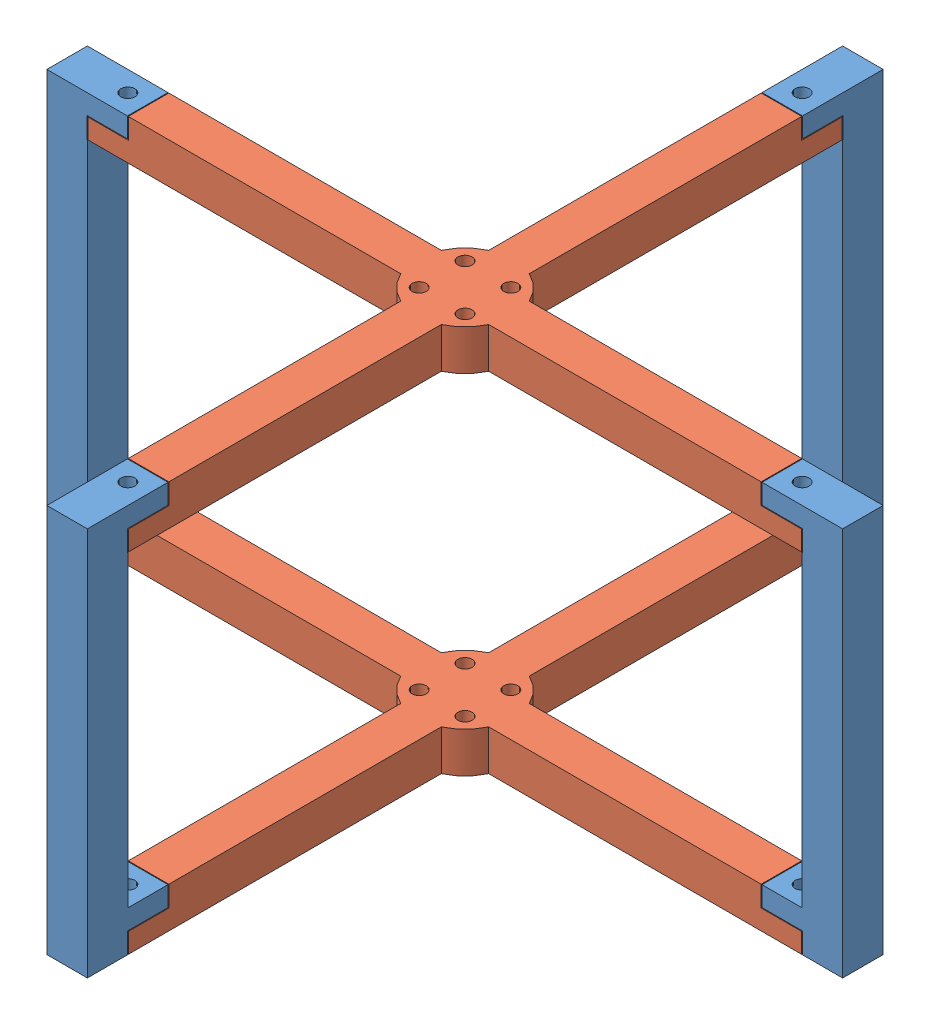
SolidWorks assembly Motor Mount Sub-Assembly, configuration Default. Lengths in mm.
Overall size (196.4 96 196.4).
6 component instances, 2 part files, 17 mates.
Components (placement in the parent):
- Motor Mount Sides-1: Motor Mount Sides [Default] at (110.7628 17.1538 16.3043) size (19.9 96 10)
- Motor Mount Sides-3: Motor Mount Sides [Default] at (27.5628 17.1538 -76.8957) x (0 0 -1) z (1 0 0) size (19.9 96 10)
- Motor Mount Upper-Lower-2: Motor Mount Upper-Lower [Default] at (22.5628 103.1538 11.3043) size (176.2 10 176.2)
- Motor Mount Upper-Lower-3: Motor Mount Upper-Lower [Default] at (22.5628 17.1538 11.3043) size (176.2 10 176.2)
- Motor Mount Sides-4: Motor Mount Sides [Default] at (-65.6372 17.1538 6.3043) x (-1 0 0) z (0 0 -1) size (19.9 96 10)
- Motor Mount Sides-5: Motor Mount Sides [Default] at (17.5628 17.1538 99.5043) x (0 0 1) z (-1 0 0) size (19.9 96 10)
Mates (geometry in assembly coordinates):
- Distance1: distance = 0.2 mm anti-aligned: plane of Motor Mount Sides-1 through (100.8628 108.2538 6.3043) normal (0 -1 0); plane of Motor Mount Upper-Lower-2 through (110.6628 108.0538 -0.6457) normal (0 1 0)
- Parallel1: parallel anti-aligned: plane of Motor Mount Sides-1 through (110.8628 108.2538 6.3043) normal (-1 0 0); plane of Motor Mount Upper-Lower-2 through (110.6628 103.1538 -0.6457) normal (1 0 0)
- Concentric3: concentric anti-aligned: cylinder of Motor Mount Sides-1 through (105.7628 113.1538 11.3043) axis (0 -1 0) radius 1.75; cylinder of Motor Mount Upper-Lower-2 through (105.7628 98.0538 11.3043) axis (0 1 0) radius 1.75
- Parallel2: parallel anti-aligned: plane of Motor Mount Sides-1 through (100.8628 27.1538 6.3043) normal (-1 0 0); plane of Motor Mount Upper-Lower-3 through (110.6628 17.1538 -0.6457) normal (1 0 0)
- Distance2: distance = 0.2 mm anti-aligned: plane of Motor Mount Sides-1 through (110.8628 22.2538 6.3043) normal (-1 0 0); plane of Motor Mount Upper-Lower-3 through (110.6628 17.1538 -0.6457) normal (1 0 0)
- Parallel3: parallel anti-aligned: cylinder of Motor Mount Sides-1 through (105.7628 113.1538 11.3043) axis (0 -1 0) radius 1.75; cylinder of Motor Mount Upper-Lower-3 through (105.7628 12.0538 11.3043) axis (0 1 0) radius 1.75
- Distance3: distance = 0.2 mm anti-aligned: plane of Motor Mount Upper-Lower-3 through (110.6628 22.0538 -0.6457) normal (0 1 0); plane of Motor Mount Sides-1 through (100.8628 22.2538 6.3043) normal (0 -1 0)
- Coincident6: coincident aligned: plane of Motor Mount Sides-1 through (110.7628 17.1538 16.3043) normal (0 0 1); plane of Motor Mount Upper-Lower-3 through (33.4165 -70.7631 16.3043) normal (0 0 1)
- Parallel5: parallel anti-aligned: plane of Motor Mount Sides-3 through (17.5628 113.1538 -66.9957) normal (0 0 1); plane of Motor Mount Upper-Lower-2 through (-75.6372 108.0538 -66.7957) normal (0 0 -1)
- Distance4: distance = 0.2 mm anti-aligned: plane of Motor Mount Sides-3 through (17.5628 108.2538 -66.9957) normal (0 -1 0); plane of Motor Mount Upper-Lower-2 through (-75.6372 108.0538 -76.7957) normal (0 1 0)
- Concentric6: concentric anti-aligned: cylinder of Motor Mount Sides-3 through (22.5628 113.1538 -71.8957) axis (0 -1 0) radius 1.75; cylinder of Motor Mount Upper-Lower-2 through (22.5628 98.0538 -71.8957) axis (0 1 0) radius 1.75
- Parallel6: parallel anti-aligned: plane of Motor Mount Upper-Lower-2 through (-55.5372 108.0538 109.5043) normal (-1 0 0); plane of Motor Mount Sides-4 through (-55.7372 113.1538 16.3043) normal (1 0 0)
- Distance5: distance = 0.2 mm anti-aligned: plane of Motor Mount Sides-4 through (-55.7372 108.2538 16.3043) normal (0 -1 0); plane of Motor Mount Upper-Lower-2 through (-65.5372 108.0538 109.5043) normal (0 1 0)
- Concentric7: concentric anti-aligned: cylinder of Motor Mount Upper-Lower-2 through (-60.6372 98.0538 11.3043) axis (0 1 0) radius 1.75; cylinder of Motor Mount Sides-4 through (-60.6372 113.1538 11.3043) axis (0 -1 0) radius 1.75
- Parallel7: parallel anti-aligned: plane of Motor Mount Upper-Lower-2 through (110.6628 108.0538 89.4043) normal (0 0 1); plane of Motor Mount Sides-5 through (27.5628 113.1538 89.6043) normal (0 0 -1)
- Distance6: distance = 0.2 mm anti-aligned: plane of Motor Mount Upper-Lower-2 through (110.6628 108.0538 99.4043) normal (0 1 0); plane of Motor Mount Sides-5 through (27.5628 108.2538 89.6043) normal (0 -1 0)
- Concentric8: concentric anti-aligned: circle of Motor Mount Upper-Lower-2; cylinder of Motor Mount Sides-5 through (22.5628 113.1538 94.5043) axis (0 -1 0) radius 1.75
